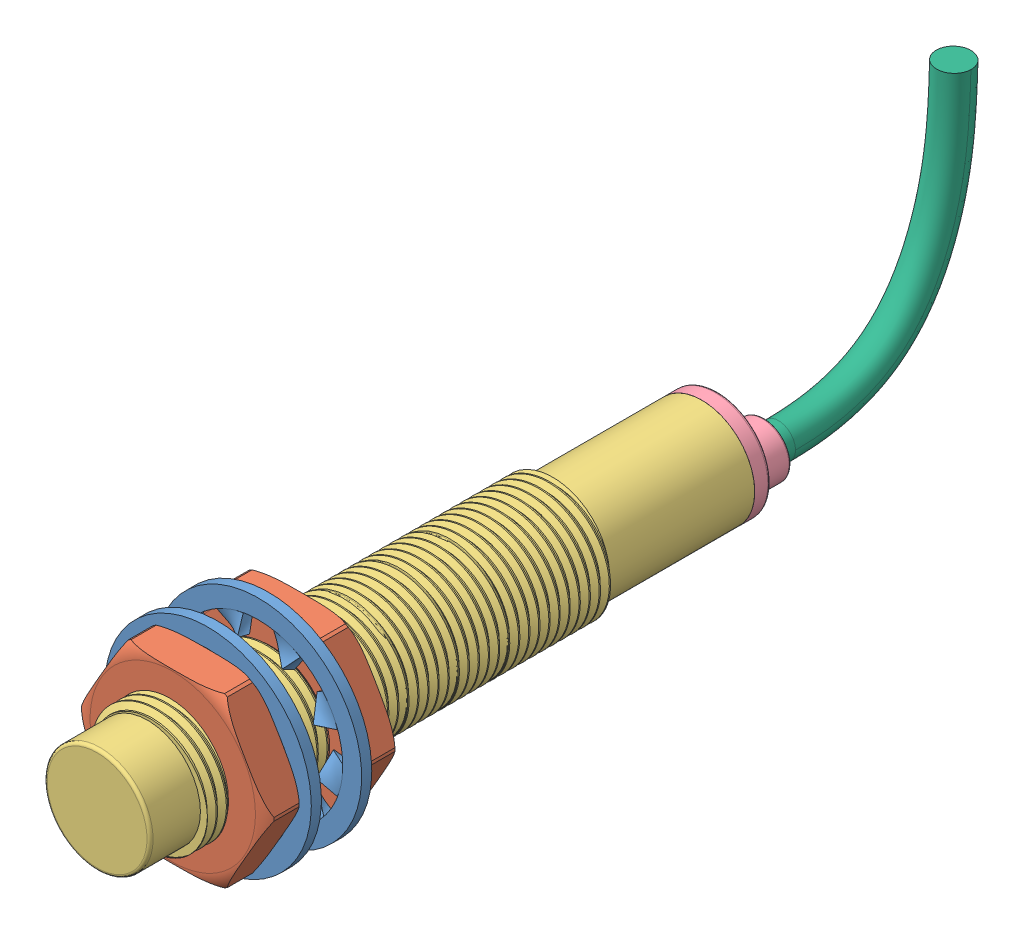
SolidWorks assembly homing_sensor, configuration Default. Lengths in mm.
Overall size (20.5 32.31 86.91).
9 component instances, 6 part files, 0 mates.
Components (placement in the parent):
- homing_sensor.step-1: homing_sensor.step [Default] at origin size (20.5 32.31 86.91)
  - 93925A300.step-1: 93925A300.step [Default] at (-0.0005 -0.0003 -11.5) x (1 0 0) z (0 0 -1) size (20.5 20.5 2.11)
  - 93925A300.step-2: 93925A300.step [Default] at (-0.0006 -0.0007 -16.5) x (1 0 0) z (0 0 -1) size (20.5 20.5 2.11)
  - Nut.step-1: Nut.step [Default] at (-0.0001 -0.0008 -11) size (19.14 16.74 3.53)
  - Nut.step-2: Nut.step [Default] at (-0.0004 -0.0002 -17) x (1 0 0) z (0 0 -1) size (19.14 16.74 3.53)
  - LJ12A3-4-Z_BX.step-1: LJ12A3-4-Z_BX.step [Default] at origin size (12.05 12.05 60)
  - LJ12A3-4-Z_BX-0.step-1: LJ12A3-4-Z_BX-0.step [Default] at origin size (10.5 10.5 6.2)
  - LJ12A3-4-Z_BX-1.step-1: LJ12A3-4-Z_BX-1.step [Default] at origin size (3.5 3.5 1.5)
  - LJ12A3-4-Z_BX-2.step-1: LJ12A3-4-Z_BX-2.step [Default] at origin size (3.54 25.97 25.31)
